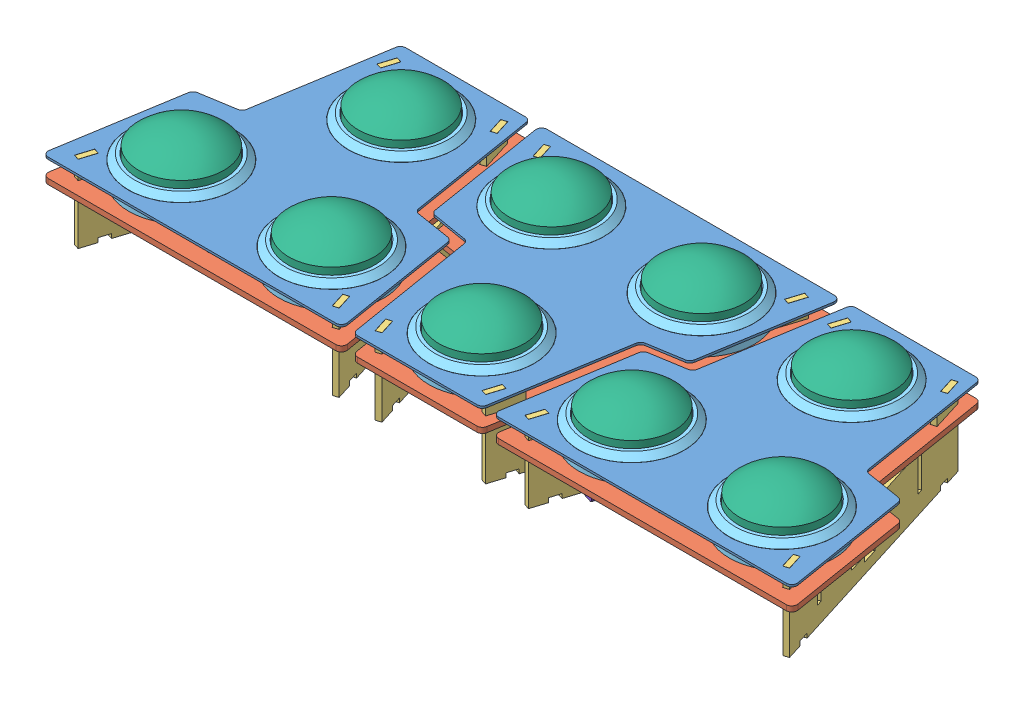
SolidWorks assembly Assembly, configuration Default. Lengths in mm.
Overall size (698.24 99.55 255).
55 component instances, 8 part files, 71 mates.
Components (placement in the parent):
- Top Plate-1: Top Plate [Default] at (171.8123 -27.9169 -109.6293) x (-1 0 0) z (0 0 -1) size (278.24 2 255)
- Top Plate-2: Top Plate [Default] at (381.8123 -27.9169 145.3707) size (278.24 2 255)
- Top Plate-3: Top Plate [Default] at (-38.1877 -27.9169 145.3707) size (278.24 2 255)
- Middle Plate-1: Middle Plate [Default] at (171.8123 -48.1669 -109.6293) x (-1 0 0) z (0 0 -1) size (278.24 5 255)
- Middle Plate-2: Middle Plate [Default] at (381.8123 -48.1669 145.3707) size (278.24 5 255)
- Middle Plate-3: Middle Plate [Default] at (-38.1877 -48.1669 145.3707) size (278.24 5 255)
- Support-1: Support [Default] at (500.3477 -98.1669 133.1166) x (-0.29934 0 -0.954146) z (0.954146 0 -0.29934) size (240 72.25 5)
- Support-2: Support [Default] at (258.5061 -98.1669 131.6199) x (0.29934 0 -0.954146) z (0.954146 0 0.29934) size (240 72.25 5)
- Support-3: Support [Default] at (295.1184 -98.1669 -95.8785) x (-0.29934 0 0.954146) z (-0.954146 0 -0.29934) size (240 72.25 5)
- Support-5: Support [Default] at (53.2768 -98.1669 -97.3752) x (0.29934 0 0.954146) z (-0.954146 0 0.29934) size (240 72.25 5)
- Support-6: Support [Default] at (-161.4939 -98.1669 131.6199) x (0.29934 0 -0.954146) z (0.954146 0 0.29934) size (240 72.25 5)
- Support-7: Support [Default] at (80.3477 -98.1669 133.1166) x (-0.29934 0 -0.954146) z (0.954146 0 -0.29934) size (240 72.25 5)
- Electronics-1: Electronics [Default] at (145.2769 -66.1669 -90.9984) size (50 18 50)
- Button Assembly-1: Button Assembly [Default] at (-112.1939 -47.0453 93.2547) size (98 92.55 98)
  - Button Shield-2: Button Shield [Default] at (4.0062 3.8785 -7.884) size (98 47.5 98)
  - Button Dome-2: Button Dome [Default] at (4.0062 19.9285 -7.884) size (79.5 28.5 79.5)
  - Microswitch-2: Microswitch [Default] at (4.0062 -39.6215 -21.634) x (0 0 1) z (-1 0 0) size (38 41 20)
- Button Assembly-2: Button Assembly [Default] at (-42.1939 -47.0453 -41.7453) size (98 92.55 98)
  - Button Shield-2: Button Shield [Default] at (4.0062 3.8785 -7.884) size (98 47.5 98)
  - Button Dome-2: Button Dome [Default] at (4.0062 19.9285 -7.884) size (79.5 28.5 79.5)
  - Microswitch-2: Microswitch [Default] at (4.0062 -39.6215 -21.634) x (0 0 1) z (-1 0 0) size (38 41 20)
- Button Assembly-3: Button Assembly [Default] at (27.8061 -47.0453 93.2547) size (98 92.55 98)
  - Button Shield-2: Button Shield [Default] at (4.0062 3.8785 -7.884) size (98 47.5 98)
  - Button Dome-2: Button Dome [Default] at (4.0062 19.9285 -7.884) size (79.5 28.5 79.5)
  - Microswitch-2: Microswitch [Default] at (4.0062 -39.6215 -21.634) x (0 0 1) z (-1 0 0) size (38 41 20)
- Button Assembly-4: Button Assembly [Default] at (97.8061 -47.0453 -41.7453) size (98 92.55 98)
  - Button Shield-2: Button Shield [Default] at (4.0062 3.8785 -7.884) size (98 47.5 98)
  - Button Dome-2: Button Dome [Default] at (4.0062 19.9285 -7.884) size (79.5 28.5 79.5)
  - Microswitch-2: Microswitch [Default] at (4.0062 -39.6215 -21.634) x (0 0 1) z (-1 0 0) size (38 41 20)
- Button Assembly-5: Button Assembly [Default] at (167.8061 -47.0453 93.2547) size (98 92.55 98)
  - Button Shield-2: Button Shield [Default] at (4.0062 3.8785 -7.884) size (98 47.5 98)
  - Button Dome-2: Button Dome [Default] at (4.0062 19.9285 -7.884) size (79.5 28.5 79.5)
  - Microswitch-2: Microswitch [Default] at (4.0062 -39.6215 -21.634) x (0 0 1) z (-1 0 0) size (38 41 20)
- Button Assembly-6: Button Assembly [Default] at (237.8061 -47.0453 -41.7453) size (98 92.55 98)
  - Button Shield-2: Button Shield [Default] at (4.0062 3.8785 -7.884) size (98 47.5 98)
  - Button Dome-2: Button Dome [Default] at (4.0062 19.9285 -7.884) size (79.5 28.5 79.5)
  - Microswitch-2: Microswitch [Default] at (4.0062 -39.6215 -21.634) x (0 0 1) z (-1 0 0) size (38 41 20)
- Button Assembly-7: Button Assembly [Default] at (307.8061 -47.0453 93.2547) size (98 92.55 98)
  - Button Shield-2: Button Shield [Default] at (4.0062 3.8785 -7.884) size (98 47.5 98)
  - Button Dome-2: Button Dome [Default] at (4.0062 19.9285 -7.884) size (79.5 28.5 79.5)
  - Microswitch-2: Microswitch [Default] at (4.0062 -39.6215 -21.634) x (0 0 1) z (-1 0 0) size (38 41 20)
- Button Assembly-8: Button Assembly [Default] at (377.8061 -47.0453 -41.7453) size (98 92.55 98)
  - Button Shield-2: Button Shield [Default] at (4.0062 3.8785 -7.884) size (98 47.5 98)
  - Button Dome-2: Button Dome [Default] at (4.0062 19.9285 -7.884) size (79.5 28.5 79.5)
  - Microswitch-2: Microswitch [Default] at (4.0062 -39.6215 -21.634) x (0 0 1) z (-1 0 0) size (38 41 20)
- Button Assembly-9: Button Assembly [Default] at (447.8061 -47.0453 93.2547) size (98 92.55 98)
  - Button Shield-2: Button Shield [Default] at (4.0062 3.8785 -7.884) size (98 47.5 98)
  - Button Dome-2: Button Dome [Default] at (4.0062 19.9285 -7.884) size (79.5 28.5 79.5)
  - Microswitch-2: Microswitch [Default] at (4.0062 -39.6215 -21.634) x (0 0 1) z (-1 0 0) size (38 41 20)
- Vertical Interlock-1: Vertical Interlock [Default] at (54.0943 -98.1669 94.2559) x (0.954146 0 -0.29934) z (0.29934 0 0.954146) size (70 50 5)
- Vertical Interlock-2: Vertical Interlock [Default] at (11.262 -98.1669 -42.2718) x (0.954146 0 -0.29934) z (0.29934 0 0.954146) size (70 50 5)
- Vertical Interlock-3: Vertical Interlock [Default] at (265.5722 -98.1669 -63.2256) x (0.954146 0 0.29934) z (-0.29934 0 0.954146) size (70 50 5)
- Vertical Interlock-4: Vertical Interlock [Default] at (222.7587 -98.1669 73.2425) x (0.954146 0 0.29934) z (-0.29934 0 0.954146) size (70 50 5)
- Vertical Interlock-5: Vertical Interlock [Default] at (250.9006 -83.1669 -16.4599) x (0.954146 0 0.29934) z (0 -1 0) size (70 50 5)
- Vertical Interlock-6: Vertical Interlock [Default] at (25.9336 -83.1669 4.4939) x (0.954146 0 -0.29934) z (0 -1 0) size (70 50 5)
Mates (geometry in assembly coordinates):
- Coincident1: coincident aligned: plane of Top Plate-1 through (287.7204 -27.9169 7.0789) normal (0 -1 0); plane of Top Plate-2 through (265.9041 -27.9169 28.6625) normal (0 -1 0)
- Coincident2: coincident aligned: plane of Top Plate-1 through (287.7204 -27.9169 7.0789) normal (0 -1 0); plane of Top Plate-3 through (-154.0959 -27.9169 28.6625) normal (0 -1 0)
- Coincident3: coincident aligned: plane of Top Plate-1 through (227.5614 -25.9169 145.3707) normal (0 0 1); plane of Top Plate-2 through (247.6934 -25.9169 145.3707) normal (0 0 1)
- Coincident4: coincident aligned: plane of Top Plate-1 through (227.5614 -25.9169 145.3707) normal (0 0 1); plane of Top Plate-3 through (-172.3066 -25.9169 145.3707) normal (0 0 1)
- Distance1: distance = 210 mm: line of Top Plate-2 through (381.8123 -25.9169 145.3707) axis (0 0 -1); line of Top Plate-1 through (171.8123 -25.9169 -109.6293) axis (0 0 1)
- Distance2: distance = 210 mm: line of Top Plate-1 through (171.8123 -25.9169 -109.6293) axis (0 0 1); line of Top Plate-3 through (-38.1877 -25.9169 145.3707) axis (0 0 -1)
- Coincident5: coincident aligned: plane of Top Plate-1 through (305.9312 -25.9169 -109.6293) normal (0 0 -1); plane of Middle Plate-1 through (305.9312 -43.1669 -109.6293) normal (0 0 -1)
- Coincident6: coincident aligned: plane of Top Plate-2 through (247.6934 -25.9169 145.3707) normal (0 0 1); plane of Middle Plate-2 through (247.6934 -43.1669 145.3707) normal (0 0 1)
- Coincident7: coincident aligned: plane of Top Plate-3 through (-172.3066 -25.9169 145.3707) normal (0 0 1); plane of Middle Plate-3 through (-172.3066 -43.1669 145.3707) normal (0 0 1)
- Coincident8: coincident aligned: plane of Middle Plate-1 through (116.0632 -43.1669 140.3707) normal (0 1 0); plane of Middle Plate-3 through (17.5614 -43.1669 -104.6293) normal (0 1 0)
- Coincident10: coincident aligned: plane of Middle Plate-1 through (116.0632 -43.1669 140.3707) normal (0 1 0); plane of Middle Plate-2 through (437.5614 -43.1669 -104.6293) normal (0 1 0)
- Concentric2: concentric aligned: circle of Top Plate-3; circle of Middle Plate-3
- Concentric3: concentric aligned: circle of Top Plate-1; circle of Middle Plate-1
- Concentric4: concentric aligned: circle of Top Plate-2; circle of Middle Plate-2
- Coincident11: coincident anti-aligned: plane of Top Plate-2 through (265.9041 -27.9169 28.6625) normal (0 -1 0); plane of Support-1 through (499.1316 -27.9169 112.537) normal (0 1 0)
- Coincident15: coincident anti-aligned: plane of Top Plate-2 through (265.9041 -27.9169 28.6625) normal (0 -1 0); plane of Support-2 through (269.2636 -27.9169 114.0337) normal (0 1 0)
- Coincident20: coincident anti-aligned: plane of Top Plate-1 through (287.7204 -27.9169 7.0789) normal (0 -1 0); plane of Support-3 through (284.3609 -27.9169 -78.2923) normal (0 1 0)
- Width2: width aligned: plane of Top Plate-2 through (500.2434 -30.9169 133.2018) normal (0.954146 0 -0.29934); plane of Top Plate-2 through (505.2527 -30.9169 131.6302) normal (-0.954146 0 0.29934); plane of Support-1 through (442.257 -48.1669 -68.7508) normal (0.954146 0 -0.29934); plane of Support-1 through (437.4863 -48.1669 -67.2541) normal (-0.954146 0 0.29934)
- Coincident38: coincident anti-aligned: plane of Top Plate-1 through (287.7204 -27.9169 7.0789) normal (0 -1 0); plane of Support-5 through (115.8576 -27.9169 118.8044) normal (0 1 0)
- Width6: width anti-aligned: plane of Top Plate-1 through (115.7234 -30.9169 118.7941) normal (0.954146 0 -0.29934); plane of Top Plate-1 through (120.7326 -30.9169 117.2226) normal (-0.954146 0 0.29934); plane of Support-5 through (111.3675 -48.1669 104.4922) normal (-0.954146 0 0.29934); plane of Support-5 through (116.1382 -48.1669 102.9955) normal (0.954146 0 -0.29934)
- Coincident40: coincident anti-aligned: plane of Top Plate-3 through (-154.0959 -27.9169 28.6625) normal (0 -1 0); plane of Support-7 through (79.1316 -27.9169 112.537) normal (0 1 0)
- Width7: width anti-aligned: plane of Top Plate-3 through (80.2434 -30.9169 133.2018) normal (0.954146 0 -0.29934); plane of Top Plate-3 through (85.2527 -30.9169 131.6302) normal (-0.954146 0 0.29934); plane of Support-7 through (17.4863 -48.1669 -67.2541) normal (-0.954146 0 0.29934); plane of Support-7 through (22.257 -48.1669 -68.7508) normal (0.954146 0 -0.29934)
- Coincident42: coincident anti-aligned: plane of Top Plate-3 through (-154.0959 -27.9169 28.6625) normal (0 -1 0); plane of Support-6 through (-89.3717 -27.9169 -81.5663) normal (0 1 0)
- Coincident56: coincident anti-aligned: plane of Middle Plate-2 through (437.5614 -48.1669 -104.6293) normal (0 -1 0); plane of Support-2 through (326.1382 -48.1669 -67.2541) normal (0 1 0)
- Coincident69: coincident anti-aligned: plane of Middle Plate-3 through (17.5614 -43.1669 -104.6293) normal (0 1 0); plane of Button Assembly-1/Button Shield-2 through (-108.1877 -43.1669 85.3707) normal (0 -1 0)
- Coincident70: coincident aligned: circle of Middle Plate-3; cylinder of Button Assembly-1/Button Shield-2 through (-108.1877 -68.1669 85.3707) axis (0 1 0) radius 12
- Coincident71: coincident anti-aligned: plane of Middle Plate-3 through (17.5614 -43.1669 -104.6293) normal (0 1 0); plane of Button Assembly-2/Button Shield-2 through (-38.1877 -43.1669 -49.6293) normal (0 -1 0)
- Coincident72: coincident aligned: circle of Middle Plate-3; cylinder of Button Assembly-2/Button Shield-2 through (-38.1877 -68.1669 -49.6293) axis (0 1 0) radius 12
- Coincident73: coincident anti-aligned: plane of Middle Plate-3 through (17.5614 -43.1669 -104.6293) normal (0 1 0); plane of Button Assembly-3/Button Shield-2 through (31.8123 -43.1669 85.3707) normal (0 -1 0)
- Coincident74: coincident aligned: circle of Middle Plate-3; cylinder of Button Assembly-3/Button Shield-2 through (31.8123 -68.1669 85.3707) axis (0 1 0) radius 12
- Coincident75: coincident anti-aligned: plane of Middle Plate-1 through (116.0632 -43.1669 140.3707) normal (0 1 0); plane of Button Assembly-4/Button Shield-2 through (101.8123 -43.1669 -49.6293) normal (0 -1 0)
- Coincident76: coincident aligned: circle of Middle Plate-1; cylinder of Button Assembly-4/Button Shield-2 through (101.8123 -68.1669 -49.6293) axis (0 1 0) radius 12
- Coincident77: coincident anti-aligned: plane of Middle Plate-1 through (116.0632 -43.1669 140.3707) normal (0 1 0); plane of Button Assembly-5/Button Shield-2 through (171.8123 -43.1669 85.3707) normal (0 -1 0)
- Coincident78: coincident aligned: circle of Middle Plate-1; cylinder of Button Assembly-5/Button Shield-2 through (171.8123 -68.1669 85.3707) axis (0 1 0) radius 12
- Coincident79: coincident anti-aligned: plane of Middle Plate-1 through (116.0632 -43.1669 140.3707) normal (0 1 0); plane of Button Assembly-6/Button Shield-2 through (241.8123 -43.1669 -49.6293) normal (0 -1 0)
- Coincident80: coincident aligned: circle of Middle Plate-1; cylinder of Button Assembly-6/Button Shield-2 through (241.8123 -68.1669 -49.6293) axis (0 1 0) radius 12
- Coincident81: coincident aligned: plane of Middle Plate-2 through (437.5614 -43.1669 -104.6293) normal (0 1 0); circle of Button Assembly-7/Button Shield-2
- Coincident82: coincident aligned: circle of Middle Plate-2; cylinder of Button Assembly-7/Button Shield-2 through (311.8123 -68.1669 85.3707) axis (0 1 0) radius 12
- Coincident83: coincident anti-aligned: plane of Middle Plate-2 through (437.5614 -43.1669 -104.6293) normal (0 1 0); plane of Button Assembly-8/Button Shield-2 through (381.8123 -43.1669 -49.6293) normal (0 -1 0)
- Coincident84: coincident aligned: circle of Middle Plate-2; cylinder of Button Assembly-8/Button Shield-2 through (381.8123 -68.1669 -49.6293) axis (0 1 0) radius 12
- Coincident85: coincident anti-aligned: plane of Middle Plate-2 through (437.5614 -43.1669 -104.6293) normal (0 1 0); plane of Button Assembly-9/Button Shield-2 through (451.8123 -43.1669 85.3707) normal (0 -1 0)
- Coincident86: coincident aligned: circle of Middle Plate-2; cylinder of Button Assembly-9/Button Shield-2 through (451.8123 -68.1669 85.3707) axis (0 1 0) radius 12
- Width9: width anti-aligned: plane of Top Plate-1 through (227.9012 -30.9169 118.7941) normal (-0.954146 0 -0.29934); plane of Top Plate-1 through (222.8919 -30.9169 117.2226) normal (0.954146 0 0.29934); plane of Support-3 through (232.257 -48.1669 104.4922) normal (0.954146 0 0.29934); plane of Support-3 through (227.4863 -48.1669 102.9955) normal (-0.954146 0 -0.29934)
- Coincident88: coincident aligned: plane of Support-7 through (85.1184 -98.1669 131.6199) normal (0 -1 0); plane of Vertical Interlock-1 through (57.4992 -98.1669 98.428) normal (0 -1 0)
- Coincident89: coincident anti-aligned: plane of Support-7 through (48.2699 -80.8669 101.3235) normal (-0.29934 0 -0.954146); plane of Vertical Interlock-1 through (120.4729 -50.1669 78.6716) normal (0.29934 0 0.954146)
- Width10: width aligned: plane of Support-7 through (17.4863 -48.1669 -67.2541) normal (-0.954146 0 0.29934); plane of Support-5 through (116.1382 -48.1669 102.9955) normal (0.954146 0 -0.29934); plane of Vertical Interlock-1 through (55.591 -96.1669 99.0267) normal (-0.954146 0 0.29934); plane of Vertical Interlock-1 through (122.3812 -96.1669 78.0729) normal (0.954146 0 -0.29934)
- Width12: width anti-aligned: plane of Top Plate-2 through (325.7234 -30.9169 -83.0527) normal (0.954146 0 0.29934); plane of Top Plate-2 through (330.7326 -30.9169 -81.4812) normal (-0.954146 0 -0.29934); plane of Support-2 through (326.1382 -48.1669 -67.2541) normal (0.954146 0 0.29934); plane of Support-2 through (321.3675 -48.1669 -68.7508) normal (-0.954146 0 -0.29934)
- Coincident92: coincident aligned: plane of Support-7 through (85.1184 -98.1669 131.6199) normal (0 -1 0); plane of Vertical Interlock-2 through (14.667 -98.1669 -38.0998) normal (0 -1 0)
- Width13: width anti-aligned: plane of Support-7 through (44.0588 -80.8669 -52.6265) normal (0.29934 0 0.954146); plane of Support-7 through (45.593 -80.8669 -47.7365) normal (-0.29934 0 -0.954146); plane of Vertical Interlock-2 through (76.144 -50.1669 -62.627) normal (-0.29934 0 -0.954146); plane of Vertical Interlock-2 through (77.6407 -50.1669 -57.8562) normal (0.29934 0 0.954146)
- Width14: width anti-aligned: plane of Support-7 through (17.4863 -48.1669 -67.2541) normal (-0.954146 0 0.29934); plane of Support-5 through (116.1382 -48.1669 102.9955) normal (0.954146 0 -0.29934); plane of Vertical Interlock-2 through (79.549 -96.1669 -58.4549) normal (0.954146 0 -0.29934); plane of Vertical Interlock-2 through (12.7587 -96.1669 -37.5011) normal (-0.954146 0 0.29934)
- Coincident93: coincident aligned: plane of Support-2 through (263.2768 -98.1669 133.1166) normal (0 -1 0); plane of Vertical Interlock-3 through (265.9838 -98.1669 -57.8562) normal (0 -1 0)
- Width15: width anti-aligned: plane of Support-2 through (333.2882 -80.8669 -36.6756) normal (0.29934 0 -0.954146); plane of Support-2 through (334.8223 -80.8669 -41.5656) normal (-0.29934 0 0.954146); plane of Vertical Interlock-3 through (330.4542 -50.1669 -42.8705) normal (0.29934 0 -0.954146); plane of Vertical Interlock-3 through (328.9575 -50.1669 -38.0998) normal (-0.29934 0 0.954146)
- Width16: width anti-aligned: plane of Support-3 through (227.4863 -48.1669 102.9955) normal (-0.954146 0 -0.29934); plane of Support-2 through (326.1382 -48.1669 -67.2541) normal (0.954146 0 0.29934); plane of Vertical Interlock-3 through (264.0755 -96.1669 -58.4549) normal (-0.954146 0 -0.29934); plane of Vertical Interlock-3 through (330.8658 -96.1669 -37.5011) normal (0.954146 0 0.29934)
- Coincident94: coincident aligned: plane of Support-2 through (263.2768 -98.1669 133.1166) normal (0 -1 0); plane of Vertical Interlock-4 through (223.1703 -98.1669 78.6119) normal (0 -1 0)
- Width17: width anti-aligned: plane of Support-2 through (251.8722 -80.8669 82.3106) normal (-0.29934 0 0.954146); plane of Support-2 through (250.338 -80.8669 87.2006) normal (0.29934 0 -0.954146); plane of Vertical Interlock-4 through (286.144 -50.1669 98.3684) normal (-0.29934 0 0.954146); plane of Vertical Interlock-4 through (287.6407 -50.1669 93.5976) normal (0.29934 0 -0.954146)
- Width18: width anti-aligned: plane of Support-3 through (227.4863 -48.1669 102.9955) normal (-0.954146 0 -0.29934); plane of Support-2 through (326.1382 -48.1669 -67.2541) normal (0.954146 0 0.29934); plane of Vertical Interlock-4 through (221.262 -96.1669 78.0132) normal (-0.954146 0 -0.29934); plane of Vertical Interlock-4 through (288.0523 -96.1669 98.967) normal (0.954146 0 0.29934)
- Width19: width anti-aligned: plane of Top Plate-2 through (325.7234 -30.9169 -83.0527) normal (0.954146 0 0.29934); plane of Top Plate-2 through (330.7326 -30.9169 -81.4812) normal (-0.954146 0 -0.29934); plane of Support-2 through (321.3675 -48.1669 -68.7508) normal (-0.954146 0 -0.29934); plane of Support-2 through (326.1382 -48.1669 -67.2541) normal (0.954146 0 0.29934)
- Width20: width anti-aligned: plane of Top Plate-3 through (-94.2766 -30.9169 -83.0527) normal (0.954146 0 0.29934); plane of Top Plate-3 through (-89.2674 -30.9169 -81.4812) normal (-0.954146 0 -0.29934); plane of Support-6 through (-98.6325 -48.1669 -68.7508) normal (-0.954146 0 -0.29934); plane of Support-6 through (-93.8618 -48.1669 -67.2541) normal (0.954146 0 0.29934)
- Width21: width aligned: plane of Top Plate-3 through (-89.7566 -30.9169 -97.4603) normal (-0.29934 0 0.954146); plane of Top Plate-3 through (-156.6189 -30.9169 133.2018) normal (0.29934 0 -0.954146); plane of Support-6 through (-156.7232 -25.9169 133.1166) normal (-0.29934 0 0.954146); plane of Support-6 through (-84.8816 -98.1669 -95.8785) normal (0.29934 0 -0.954146)
- Width22: width anti-aligned: plane of Top Plate-3 through (80.2434 -30.9169 133.2018) normal (-0.29934 0 -0.954146); plane of Top Plate-3 through (13.3811 -30.9169 -97.4603) normal (0.29934 0 0.954146); plane of Support-7 through (85.1184 -25.9169 131.6199) normal (0.29934 0 0.954146); plane of Support-7 through (13.2768 -98.1669 -97.3752) normal (-0.29934 0 -0.954146)
- Width23: width anti-aligned: plane of Top Plate-1 through (120.2434 -30.9169 133.2018) normal (-0.29934 0 -0.954146); plane of Top Plate-1 through (53.3811 -30.9169 -97.4603) normal (0.29934 0 0.954146); plane of Support-5 through (120.3477 -98.1669 133.1166) normal (0.29934 0 0.954146); plane of Support-5 through (48.5061 -25.9169 -95.8785) normal (-0.29934 0 -0.954146)
- Width24: width anti-aligned: plane of Top Plate-2 through (500.2434 -30.9169 133.2018) normal (-0.29934 0 -0.954146); plane of Top Plate-2 through (433.3811 -30.9169 -97.4603) normal (0.29934 0 0.954146); plane of Support-1 through (505.1184 -25.9169 131.6199) normal (0.29934 0 0.954146); plane of Support-1 through (433.2768 -98.1669 -97.3752) normal (-0.29934 0 -0.954146)
- Width25: width anti-aligned: plane of Top Plate-2 through (263.3811 -30.9169 133.2018) normal (0.29934 0 -0.954146); plane of Top Plate-2 through (330.2434 -30.9169 -97.4603) normal (-0.29934 0 0.954146); plane of Support-2 through (263.2768 -25.9169 133.1166) normal (-0.29934 0 0.954146); plane of Support-2 through (335.1184 -98.1669 -95.8785) normal (0.29934 0 -0.954146)
- Width26: width aligned: plane of Top Plate-1 through (223.3811 -30.9169 133.2018) normal (0.29934 0 -0.954146); plane of Top Plate-1 through (290.2434 -30.9169 -97.4603) normal (-0.29934 0 0.954146); plane of Support-3 through (290.3477 -25.9169 -97.3752) normal (0.29934 0 -0.954146); plane of Support-3 through (218.5061 -98.1669 131.6199) normal (-0.29934 0 0.954146)
- Coincident97: coincident anti-aligned: plane of Middle Plate-1 through (116.0632 -48.1669 140.3707) normal (0 -1 0); plane of Electronics-1 through (145.2769 -48.1669 -40.9984) normal (0 1 0)
- Coincident100: coincident anti-aligned: plane of Support-2 through (342.6096 -88.1669 30.574) normal (0 1 0); plane of Vertical Interlock-5 through (301.4143 -88.1669 49.6943) normal (0 -1 0)
- Width29: width aligned: plane of Support-2 through (342.6096 -88.1669 30.574) normal (-0.29934 0 0.954146); plane of Support-2 through (338.0746 -83.1669 45.0293) normal (0.29934 0 -0.954146); plane of Vertical Interlock-5 through (295.2201 -83.1669 31.5061) normal (-0.29934 0 0.954146); plane of Vertical Interlock-5 through (294.8202 -83.1669 15.6598) normal (0.29934 0 -0.954146)
- Width30: width anti-aligned: plane of Support-2 through (326.1382 -48.1669 -67.2541) normal (0.954146 0 0.29934); plane of Support-3 through (227.4863 -48.1669 102.9955) normal (-0.954146 0 -0.29934); plane of Vertical Interlock-5 through (250.302 -88.1669 -14.5516) normal (-0.954146 0 -0.29934); plane of Vertical Interlock-5 through (317.0922 -88.1669 6.4022) normal (0.954146 0 0.29934)
- Coincident101: coincident anti-aligned: plane of Support-7 through (91.6588 -88.1669 2.1367) normal (0 1 0); plane of Vertical Interlock-6 through (105.1839 -88.1669 29.9379) normal (0 -1 0)
- Width31: width anti-aligned: plane of Support-7 through (91.6588 -88.1669 2.1367) normal (0.29934 0 0.954146); plane of Support-7 through (96.1938 -83.1669 16.592) normal (-0.29934 0 -0.954146); plane of Vertical Interlock-6 through (43.9143 -83.1669 17.194) normal (-0.29934 0 -0.954146); plane of Vertical Interlock-6 through (48.4044 -83.1669 31.5061) normal (0.29934 0 0.954146)
- Width32: width anti-aligned: plane of Support-7 through (17.4863 -48.1669 -67.2541) normal (-0.954146 0 0.29934); plane of Support-5 through (116.1382 -48.1669 102.9955) normal (0.954146 0 -0.29934); plane of Vertical Interlock-6 through (93.3226 -88.1669 -14.5516) normal (0.954146 0 -0.29934); plane of Vertical Interlock-6 through (26.5323 -88.1669 6.4022) normal (-0.954146 0 0.29934)
